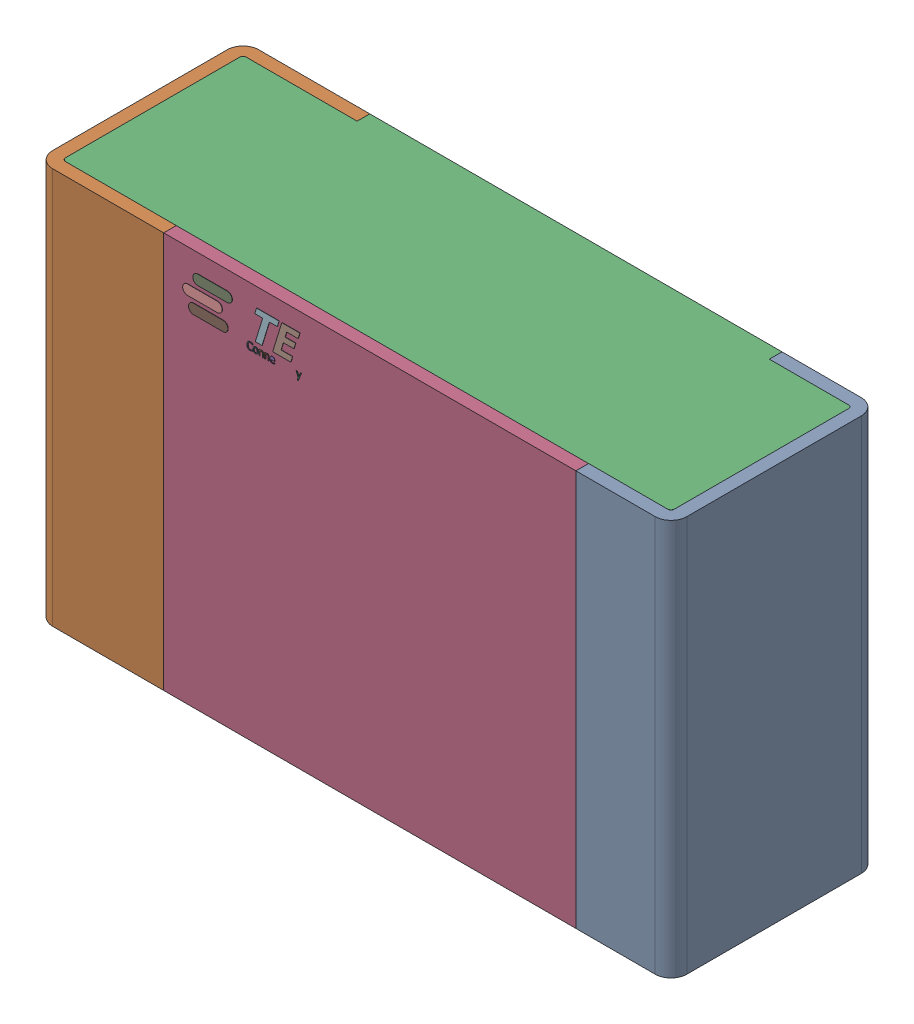
SolidWorks assembly R5.step, configuration Default. Lengths in mm.
Overall size (2 1.25 0.65).
5 component instances, 4 part files, 0 mates.
Components (placement in the parent):
- Res_TE_Connectivity_CPF0805B66R5E1_eec.step-1: Res_TE_Connectivity_CPF0805B66R5E1_eec.step [Default] at (47.244 37.592 0) size (2 1.25 0.65)
  - 1.step-1: 1.step [Default] at origin size (2 1.25 0.65)
  - 2.step-1: 2.step [Default] at origin size (1.92 1.25 0.61)
  - 3.step-1: 3.step [Default] at origin size (1.3 1.25 0.04)
  - TE connectivity Logo 1 (2).step-1: TE connectivity Logo 1 (2).step [Default] at (5.4285 0.313 0.551) x (-1 0 0) z (0 0 1) size (0.37 0.13 0.11)
